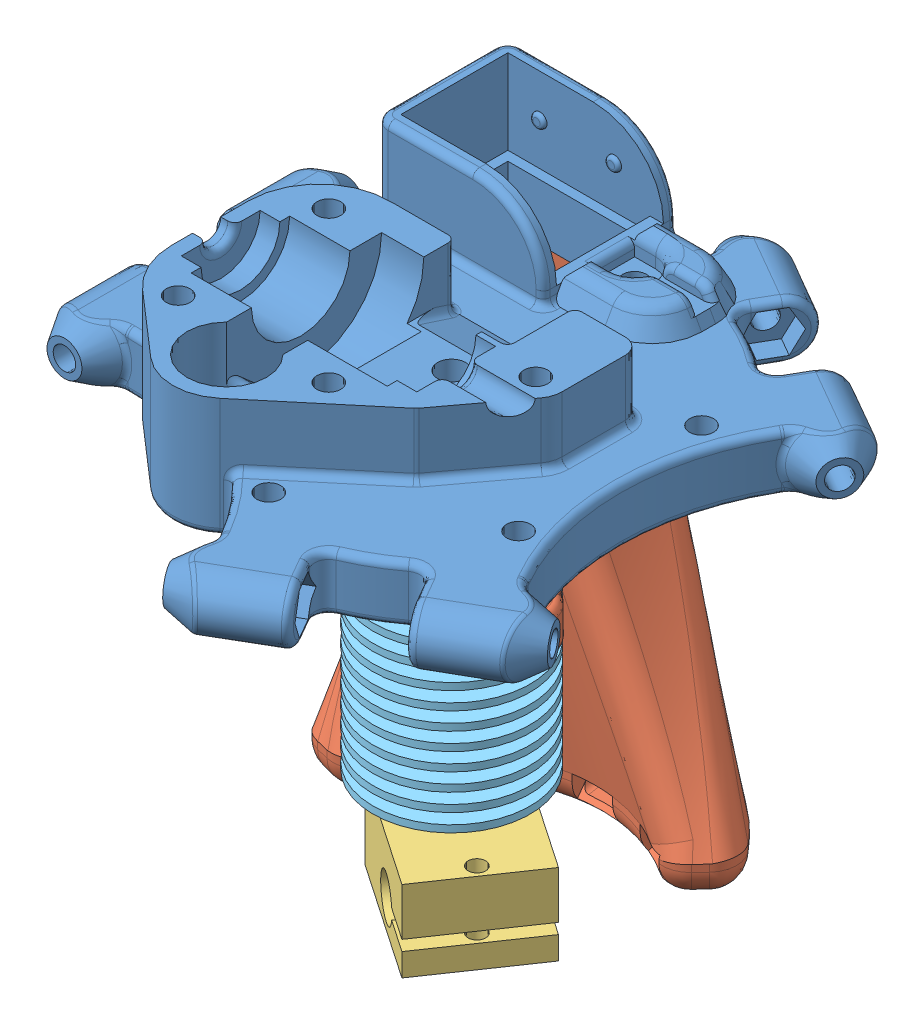
SolidWorks assembly assembled_effector, configuration FlexDrive: E3D. Lengths in mm.
Overall size (76.18 78.15 85.73).
7 component instances, 6 part files, 6 mates.
Components (placement in the parent):
- effector-1: effector [FlexDrive Bottom Fan E3D] at origin size (76.18 20.3 85.73)
- effector_clip-1: effector_clip [FanShroud] at (0 -4 0) x (0 0 -1) z (0 -1 0) size (52.83 55.85 56.31)
- hotend-e3d-v6-1: hotend-e3d-v6 [Default] at (-1.7676 -64.2278 17.9586) x (-0.825658 0 -0.564172) z (0.564172 0 -0.825658) size (26.95 61.85 22.9)
  - block^hotend-e3d-v6-1: block^hotend-e3d-v6 [Default] at (3.1723 13.0752 15.8249) size (20 12.14 16) (virtual)
  - break^hotend-e3d-v6-1: break^hotend-e3d-v6 [Default] at (8.6723 14.5752 15.8249) size (7.18 22.4 6.95) (virtual)
  - sink^hotend-e3d-v6-1: sink^hotend-e3d-v6 [Default] at (8.6723 42.5778 15.8249) x (0.999633 0 0.027082) z (-0.027082 0 0.999633) size (22.3 42.99 22.3) (virtual)
  - nozzle^hotend-e3d-v6-1: nozzle^hotend-e3d-v6 [Default] at (8.6723 2.0752 15.8249) size (7 12.82 8.08) (virtual)
Mates (geometry in assembly coordinates):
- Coincident1: coincident aligned: plane of effector-1 through (0 -4 0) normal (0 -1 0); plane of effector_clip-1 through (0 -4 0) normal (0 -1 0)
- Coincident5: coincident anti-aligned: axis of effector-1 through (0 -3 0) axis (0 1 0); line of effector_clip-1 through (0 -4 0) axis (0 -1 0)
- Parallel-Other: parallel aligned: plane of effector-1 through (0 0 0) normal (1 0 0); plane of effector_clip-1
- Concentric-flex: concentric anti-aligned: cylinder of effector-1 through (0 28 -25.9808) axis (0 -1 0) radius 1.7; cylinder of effector_clip-1 through (0 -6.5 -25.9808) axis (0 1 0) radius 1.5
- Concentric3: concentric anti-aligned: cylinder of effector-1 through (0 0.1 0) axis (0 -1 0) radius 8.2; cylinder of hotend-e3d-v6-1/sink^hotend-e3d-v6-1 through (0 1.2894 0) axis (0 1 0) radius 8
- Coincident6: coincident anti-aligned: plane of effector_clip-1 through (0 -4 0) normal (0 1 0); plane of hotend-e3d-v6-1/sink^hotend-e3d-v6-1 through (-6.4806 -4 -4.6906) normal (0 -1 0)
